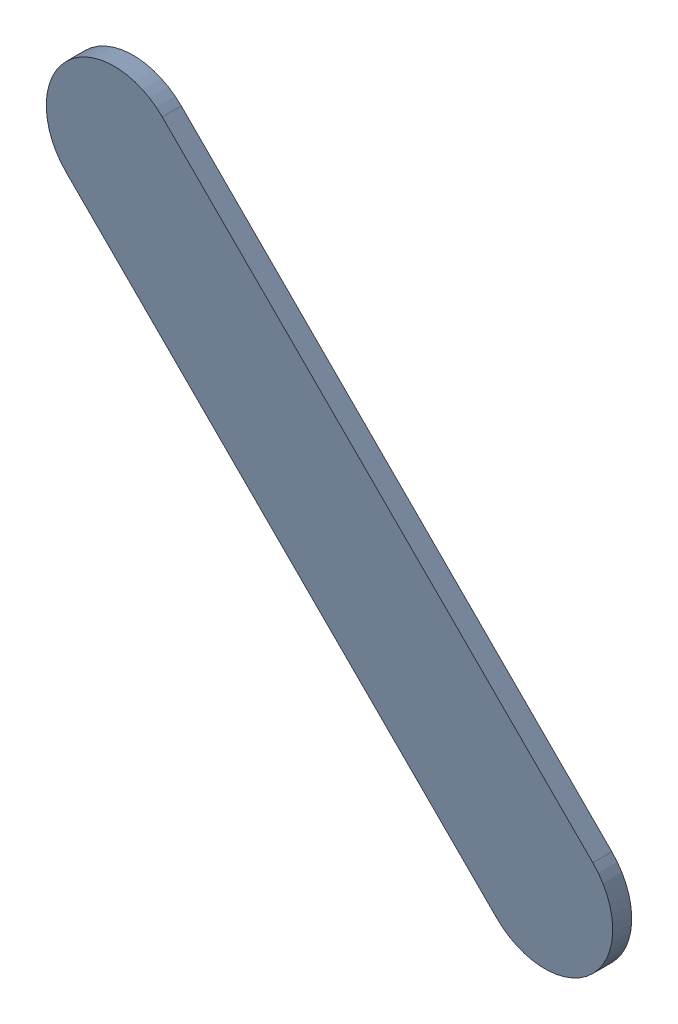
SolidWorks assembly Track (19.304mm,48.07mm)(20.109mm,47.265mm) on Bottom Layer, configuration Predeterminado. Lengths in mm.
Overall size (1.06 1.06 0.04).
2 component instances, 1 part files, 0 mates.
Components (placement in the parent):
- Track (19.304mm,48.07mm)(20.109mm,47.265mm) on Bottom Layer-1-1: Track (19.304mm,48.07mm)(20.109mm,47.265mm) on Bottom Layer-1 [Predeterminado] at (-68.317 -44.187 -0.4013) size (1.06 1.06 0.04)
  - Track (19.304mm,48.07mm)(20.109mm,47.265mm) on Bottom Layer-Part-1-1: Track (19.304mm,48.07mm)(20.109mm,47.265mm) on Bottom Layer-Part-1 [Predeterminado] at origin size (1.06 1.06 0.04)
